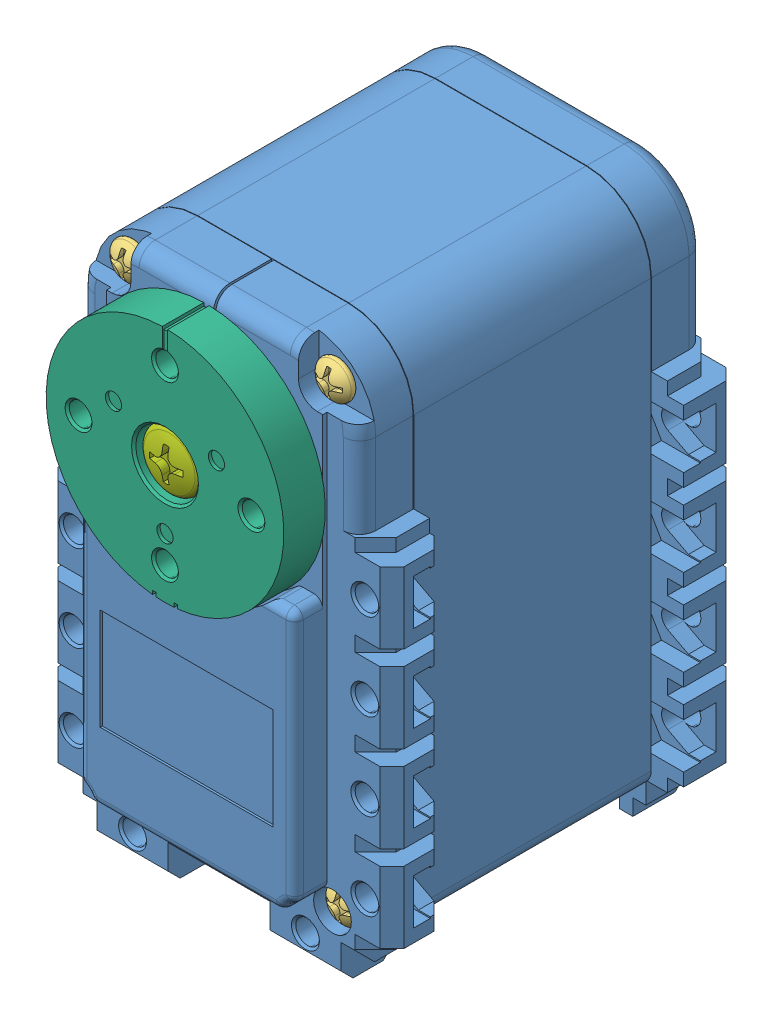
SolidWorks assembly AX-12-18-A, configuration Default. Lengths in mm.
Overall size (32 50.04 40.18).
12 component instances, 7 part files, 0 mates.
Components (placement in the parent):
- ASM0002_ASM-1: ASM0002_ASM [Default] at (-10.9914 -11.7476 -2.6432) size (32 50.04 40.18)
  - PRT0001-1: PRT0001 [Default] at origin size (32 50.04 38.06)
  - PRT0002-1: PRT0002 [Default] at (0 0 -2) x (-1 0 0) z (0 0 1) size (6.5 6.5 5.5)
  - PRT0003-1: PRT0003 [Default] at (9.5 8.5 14.5) x (-1 0 0) z (0 1 0) size (3.6 31.47 4.83)
  - PRT0003-2: PRT0003 [Default] at (-9.5 8.5 14.5) x (-1 0 0) z (0 1 0) size (3.6 31.47 4.83)
  - PRT0003-3: PRT0003 [Default] at (10.5 -33 14.5) x (-1 0 0) z (0 1 0) size (3.6 31.47 4.83)
  - PRT0003-4: PRT0003 [Default] at (-10.5 -33 14.5) x (-1 0 0) z (0 1 0) size (3.6 31.47 4.83)
  - PRT0004-1: PRT0004 [Default] at (5.05 -15.19 -9.75) x (1 0 0) z (0 1 0) size (9.9 9.43 4.9)
  - PRT0004-2: PRT0004 [Default] at (-4.95 -15.19 -9.75) x (1 0 0) z (0 1 0) size (9.9 9.43 4.9)
  - PRT0005-1: PRT0005 [Default] at (0 0 -18.4) x (-1 0 0) z (0 1 0) size (4.98 7 4.98)
  - PRT0006-1: PRT0006 [Default] at (0 0 19.16) x (0 1 0) z (0 0 1) size (22 22 6.7)
  - PRT0007-1: PRT0007 [Default] at (0 0 19.48) x (-1 0 0) z (0 1 0) size (5.5 9.69 5.91)
